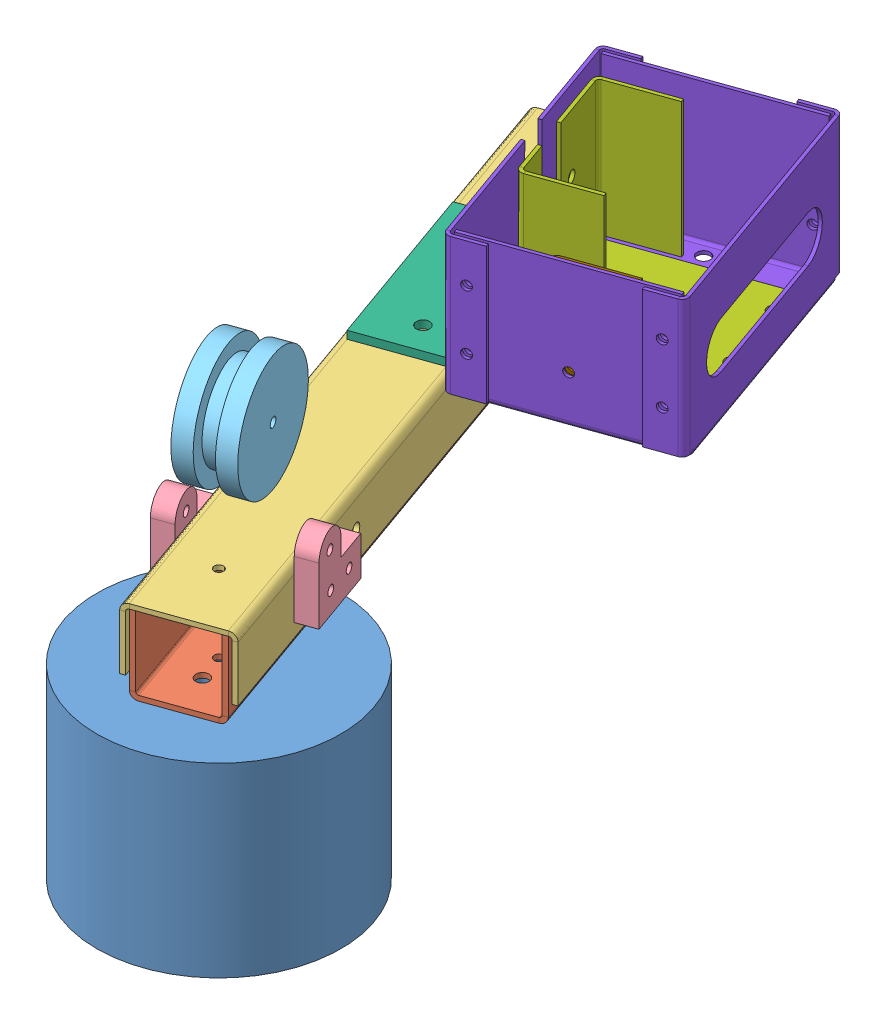
SolidWorks assembly armAssem, configuration Default. Lengths in mm.
Overall size (126.66 121.7 185.41).
11 component instances, 9 part files, 17 mates.
Components (placement in the parent):
- PlateSleeve-1: PlateSleeve [Default] at (7.5213 17.7016 55.2188) size (63 48 63)
- Boom-1: Boom [Default] at (-54.3294 85.7016 -88.8879) x (0 -1 0) z (0.335007 0 0.942216) size (20 38.5 173.5)
- top of boom-1: top of boom [Default] at (-15.8454 85.7016 -10.5008) x (-0.942216 0 0.335007) z (0.335007 0 0.942216) size (23.94 16.21 173.5)
- string roller holders-1: string roller holders [Default] at (14.8459 60.6345 40.0828) x (0.335007 0 0.942216) z (0 1 0) size (17.89 5 19.44)
- string roller holders-2: string roller holders [Default] at (-12.3373 60.6345 50.0277) x (0.335007 0 0.942216) z (0 1 0) size (17.89 5 19.44)
- string roller final-1: string roller final [Default] at (6.1555 115.4851 45.6208) x (0.11223 0.942216 0.315649) z (0.315649 -0.335007 0.88777) size (30 13.5 30)
- plate boom to spool-1: plate boom to spool [Default] at (-0.8205 86.9116 -45.8532) x (0.335007 0 0.942216) z (0.942216 0 -0.335007) size (60 2 76)
- motorbox Assembly-1: motorbox Assembly [Default] at (-38.3891 129.7336 -37.4275) x (-0.297981 0.948674 0.105948) z (0.335007 0 0.942216) size (50.54 58.37 88.68)
  - Motor Fixture-1: Motor Fixture [Default] at (-47.7174 -16.0513 13.8192) x (-0.316256 -0.948674 0) z (0 0 1) size (43 36.41 33.82)
  - Motor Gear Box V2-1: Motor Gear Box V2 [Default] at (-55.1911 -35.5927 4.6469) x (-0.316256 -0.948674 0) z (0 0 1) size (49.24 36.86 66.49)
  - encoder holder-1: encoder holder [Default] at (-55.2728 -38.557 25.4269) x (0 0 -1) z (-0.316256 -0.948674 0) size (19.96 20.86 30.86)
Mates (geometry in assembly coordinates):
- Coincident1: coincident aligned: line of PlateSleeve-1 through (5.1762 65.7016 48.6233) axis (0.335007 0 0.942216); line of Boom-1 through (-5.8293 65.7016 17.67) axis (0.335007 0 0.942216)
- Coincident2: coincident anti-aligned: plane of PlateSleeve-1 through (7.5213 65.7016 55.2188) normal (0 1 0); plane of Boom-1 through (3.7942 65.7016 74.5865) normal (0 -1 0)
- Coincident3: coincident aligned: line of PlateSleeve-1 through (-0.597 65.7016 76.1478) axis (0.942216 0 -0.335007); line of Boom-1 through (5.575 65.7016 73.9533) axis (0.942216 0 -0.335007)
- Coincident4: coincident aligned: line of Boom-1 through (22.0308 85.7016 68.1025) axis (-0.942216 0 0.335007); line of top of boom-1 through (22.6385 85.7016 67.8864) axis (-0.942216 0 0.335007)
- Coincident5: coincident anti-aligned: plane of Boom-1 through (3.7942 85.7016 74.5865) normal (0 1 0); plane of top of boom-1 through (-15.8454 85.7016 -10.5008) normal (0 -1 0)
- Coincident6: coincident aligned: line of Boom-1 through (3.7942 85.7016 74.5865) axis (-0.335007 0 -0.942216); line of top of boom-1 through (3.7942 85.7016 74.5865) axis (-0.335007 0 -0.942216)
- Coincident23: coincident anti-aligned: plane of top of boom-1 through (-4.5652 85.7016 -14.5115) normal (0.942216 0 -0.335007); plane of string roller holders-1 through (14.9447 88.9126 40.3609) normal (-0.942216 0 0.335007)
- Coincident30: coincident anti-aligned: plane of top of boom-1 through (-27.1257 85.7016 -6.4901) normal (-0.942216 0 0.335007); plane of string roller holders-2 through (-7.5273 88.9126 48.6308) normal (0.942216 0 -0.335007)
- Coincident31: coincident anti-aligned: plane of top of boom-1 through (-4.5652 85.7016 -14.5115) normal (0.942216 0 -0.335007); plane of string roller holders-1 through (14.9447 88.9126 40.3609) normal (-0.942216 0 0.335007)
- Coincident32: coincident anti-aligned: line of top of boom-1 through (24.4966 84.9396 67.2257) axis (-0.335007 0 -0.942216); line of string roller holders-1 through (13.3824 84.9396 35.9667) axis (0.335007 0 0.942216)
- Coincident33: coincident aligned: line of top of boom-1 through (-56.1875 84.9396 -88.2273) axis (0.335007 0 0.942216); line of string roller holders-2 through (-9.0897 84.9396 44.2366) axis (0.335007 0 0.942216)
- Coincident35: coincident aligned: line of string roller holders-2 through (-5.965 88.9126 53.025) axis (0 -1 0); line of assembly
- Coincident38: coincident anti-aligned: plane of top of boom-1 through (-15.8454 86.9116 -10.5008) normal (0 1 0); plane of plate boom to spool-1 through (1.0639 86.9116 -46.5232) normal (0 -1 0)
- Coincident40: coincident anti-aligned: plane of plate boom to spool-1 through (1.0639 87.7716 -46.5232) normal (0 1 0); plane of motorbox Assembly-1/Motor Gear Box V2-1 through (13.3127 87.7716 -50.8783) normal (0 -1 0)
- Coincident42: coincident anti-aligned: line of plate boom to spool-1 through (27.446 87.7716 -79.7833) axis (0.335007 0 0.942216); line of motorbox Assembly-1/Motor Gear Box V2-1 through (45.0339 87.7716 -30.317) axis (-0.335007 0 -0.942216)
- Coincident43: coincident aligned: line of plate boom to spool-1 through (10.4971 87.7716 -81.717) axis (-0.942216 0 0.335007); line of motorbox Assembly-1/Motor Gear Box V2-1 through (24.9335 87.7716 -86.8499) axis (-0.942216 0 0.335007)
- Coincident44: coincident aligned: line of top of boom-1 through (3.7942 86.9116 74.5865) axis (-0.335007 0 -0.942216); line of plate boom to spool-1 through (-27.2027 86.9116 -12.5931) axis (-0.335007 0 -0.942216)
